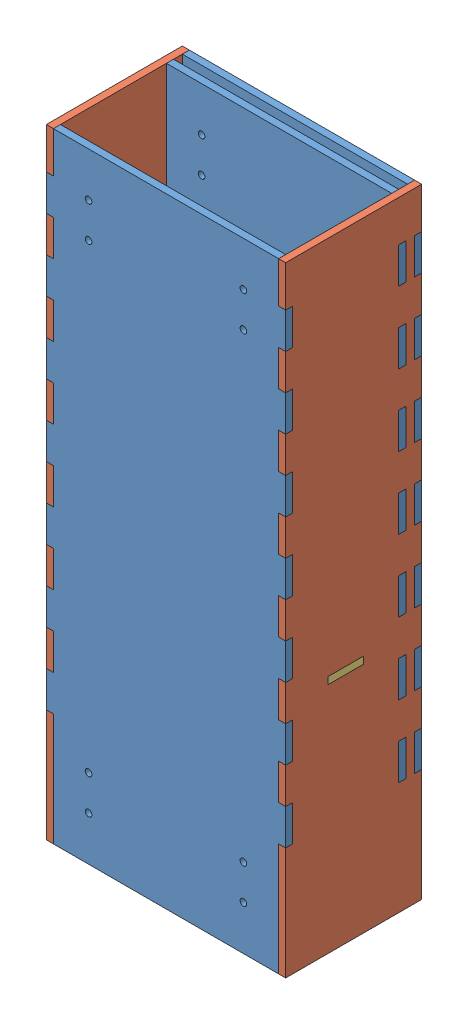
SolidWorks assembly Interaction_Box, configuration Default. Lengths in mm.
Overall size (107.95 279.4 61.35).
6 component instances, 3 part files, 15 mates.
Components (placement in the parent):
- front_back-1: front_back [Front] at (114.8789 48.9442 274.6837) size (107.95 279.4 3.17)
- side-1: side [Side] at (114.8789 48.9442 270.6837) x (0 0 1) z (-1 0 0) size (61.35 279.4 3.17)
- side-2: side [Side] at (219.6539 48.9442 270.6837) x (0 0 1) z (-1 0 0) size (61.35 279.4 3.17)
- front_back-2: front_back [Side] at (114.8789 48.9442 325.6837) size (107.95 279.4 3.17)
- front_back-3: front_back [Front] at (114.8789 48.9442 267.5087) size (107.95 279.4 3.17)
- interaction_lid-1: interaction_lid [Default] at (146.586 153.9442 295.7474) x (0 0 1) z (-1 0 0) size (47.83 3.17 107.95)
Mates (geometry in assembly coordinates):
- Coincident92: coincident aligned: plane of side-2 through (216.4789 328.3442 270.6837) normal (0 1 0); plane of front_back-2 through (114.8789 328.3442 321.8587) normal (0 1 0)
- Coincident93: coincident: plane of side-1 through (111.7039 328.3442 272.6837) normal (0 1 0); plane of front_back-2 through (114.8789 328.3442 328.8587) normal (0 1 0)
- Coincident94: coincident: plane of front_back-1 through (114.8789 328.3442 277.8587) normal (0 1 0); plane of side-1 through (111.7039 328.3442 272.6837) normal (0 1 0)
- Coincident95: coincident: plane of side-1 through (111.7039 328.3442 272.6837) normal (0 1 0); plane of front_back-3 through (114.8789 328.3442 270.6837) normal (0 1 0)
- Coincident97: coincident: plane of side-1 through (111.7039 48.9442 272.6837) normal (-1 0 0); plane of front_back-2 through (111.7039 48.9442 328.8587) normal (-1 0 0)
- Coincident98: coincident aligned: plane of side-2 through (219.6539 48.9442 270.6837) normal (1 0 0); plane of front_back-2 through (219.6539 48.9442 321.8587) normal (1 0 0)
- Coincident100: coincident anti-aligned: plane of front_back-1 through (114.8789 48.9442 277.8587) normal (0 0 1); plane of side-2 through (226.4789 309.8279 277.8587) normal (0 0 -1)
- Coincident101: coincident: plane of front_back-1 through (111.7039 48.9442 277.8587) normal (-1 0 0); plane of side-1 through (111.7039 48.9442 272.6837) normal (-1 0 0)
- Coincident102: coincident aligned: plane of side-2 through (216.4789 48.9442 267.5087) normal (0 0 -1); plane of front_back-3 through (114.8789 48.9442 267.5087) normal (0 0 -1)
- Coincident104: coincident: plane of side-1 through (111.7039 48.9442 272.6837) normal (-1 0 0); plane of front_back-3 through (111.7039 48.9442 270.6837) normal (-1 0 0)
- Coincident106: coincident aligned: plane of side-2 through (219.6539 48.9442 270.6837) normal (1 0 0); plane of interaction_lid-1 through (219.6539 137.4753 293.6912) normal (1 0 0)
- Coincident107: coincident anti-aligned: plane of side-2 through (226.4789 153.9442 293.6912) normal (0 1 0); plane of interaction_lid-1 through (146.586 153.9442 295.7474) normal (0 -1 0)
- Coincident108: coincident anti-aligned: plane of side-2 through (226.4789 157.1192 309.8512) normal (0 0 -1); plane of interaction_lid-1 through (216.4789 137.4753 309.8512) normal (0 0 1)
- Coincident109: coincident aligned: plane of side-2 through (216.4789 48.9442 328.8587) normal (0 0 1); plane of front_back-2 through (114.8789 48.9442 328.8587) normal (0 0 1)
- Coincident110: coincident aligned: plane of side-1 through (111.7039 48.9442 328.8587) normal (0 0 1); plane of front_back-2 through (114.8789 48.9442 328.8587) normal (0 0 1)
